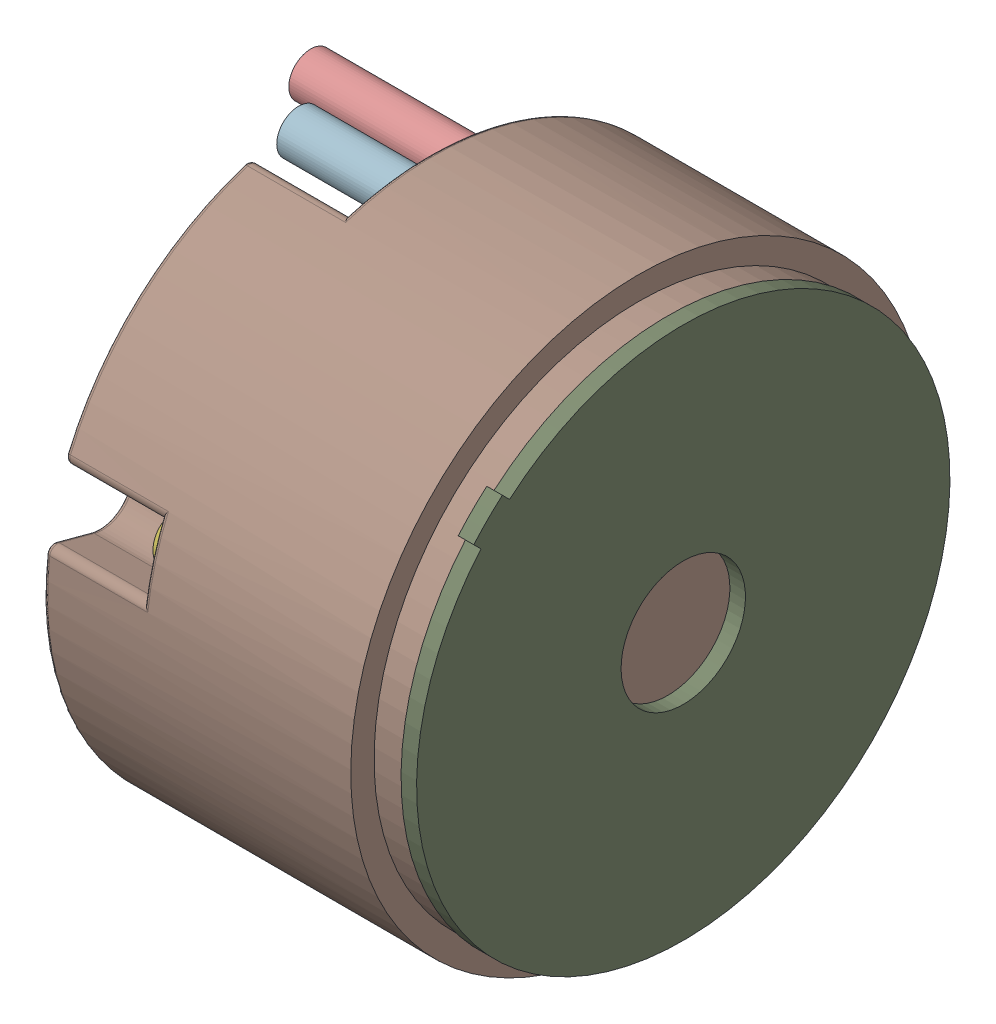
SolidWorks assembly 5000-0002-0001 encoder cap, configuration Default. Lengths in mm.
Overall size (29.66 52.33 52.33).
14 component instances, 7 part files, 0 mates.
Components (placement in the parent):
- JST-XH-4POS-VERT (1)-1: JST-XH-4POS-VERT (1) [Default] at (2.8 12.25 -75.95) x (1 0 0) z (0 0 -1) size (10.4 12.83 12.83)
  - Plastic (1)-1: Plastic (1) [Default] at (-6.1146 -33.6358 -52.1967) x (0 0.707107 0.707107) z (-1 0 0) size (12.4 5.75 7)
  - Pin (1)-1: Pin (1) [Default] at (-7.7146 -29.3225 -51.2067) x (0 0.707107 0.707107) z (-1 0 0) size (0.64 0.64 10)
  - Pin (1)-2: Pin (1) [Default] at (-7.7146 -34.6258 -56.51) x (0 0.707107 0.707107) z (-1 0 0) size (0.64 0.64 10)
  - Pin (1)-3: Pin (1) [Default] at (-7.7146 -32.858 -54.7423) x (0 0.707107 0.707107) z (-1 0 0) size (0.64 0.64 10)
  - Pin (1)-4: Pin (1) [Default] at (-7.7146 -31.0902 -52.9745) x (0 0.707107 0.707107) z (-1 0 0) size (0.64 0.64 10)
- screw-1: screw [Default] at (-41.264 -8.1646 3.9905) x (0.882398 0 0.470504) z (0 -1 0) size (8.9 7.87 4.95)
  - 99461A915_Phillips Rounded Head Thread-Forming Screws (1)-1: 99461A915_Phillips Rounded Head Thread-Forming Screws (1) [Default] at (27.264 -14.6475 -49.347) x (-0.332697 -0.623949 0.707107) z (-0.882398 0.470504 0) size (3.5 3.5 7.44)
- screw_1-1: screw_1 [Default] at (-14.4172 7.3354 3.9905) x (0.882398 0 0.470504) z (0 -1 0) size (8.9 7.87 4.95)
  - 99461A915_Phillips Rounded Head Thread-Forming Screws (1)-1: 99461A915_Phillips Rounded Head Thread-Forming Screws (1) [Default] at (-10.5142 -28.4382 -25.8237) x (-0.332697 -0.623949 0.707107) z (-0.882398 0.470504 0) size (3.5 3.5 7.44)
- endcap-1: endcap [Default] at (72.6354 37.1707 -11.0784) x (0 -0.707107 -0.707107) z (1 0 0) size (37 37 21.84)
- base-1: base [Default] at (-55.8646 37.1707 -11.0784) x (0 -0.707107 -0.707107) z (-1 0 0) size (34.96 34.31 1)
- M+-1: M+ [Default] at origin size (20.32 2.82 2.82)
- M--1: M- [Default] at (2.2506 -4.5179 -19.3049) size (20.32 2.82 2.82)
